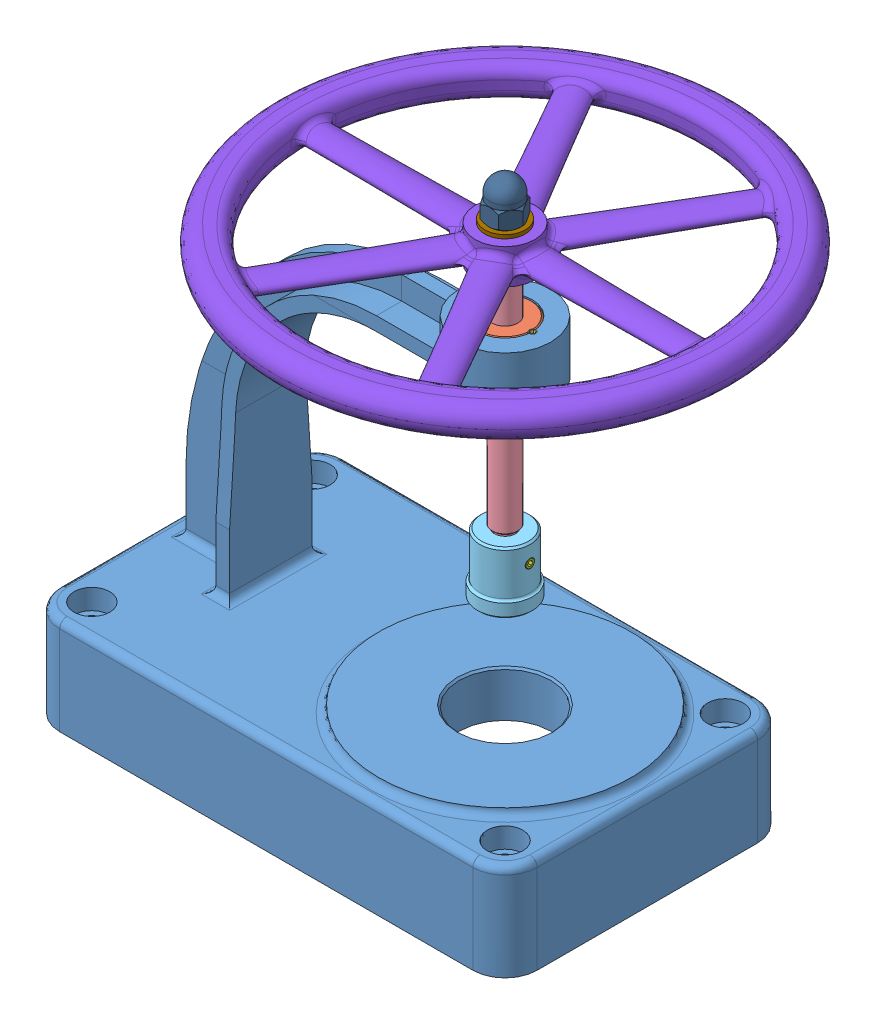
SolidWorks assembly sklop, configuration Default. Lengths in mm.
Overall size (615 613.4 500).
12 component instances, 10 part files, 33 mates.
Components (placement in the parent):
- postolje-1: postolje [Default] at (302.1555 83.8937 469.4911) size (520 480 310)
- matica-1: matica [Default] at (302.1555 493.8937 469.4911) size (70 70 70)
- vijak M8-1: vijak M8 [Default] at (272.1555 543.8937 469.4911) size (8 20 8)
- vijak M8-2: vijak M8 [Default] at (332.1555 543.8937 469.4911) size (8 20 8)
- vreteno-1: vreteno [Default] at (302.1555 323.8937 469.4911) size (36.2 353 36.2)
- glava-1: glava [Default] at (302.1555 298.8937 469.4911) x (0 0 1) z (-1 0 0) size (60 65 60)
- kuglasti oslonac-1: kuglasti oslonac [Default] at (302.1555 313.8937 469.4911) x (0 0 1) z (-1 0 0) size (21 10 21)
- vijak M10-1: vijak M10 [Default] at (274.6555 343.8937 469.4911) x (0 0 1) z (0 1 0) size (10 20 10)
- vijak M10-2: vijak M10 [Default] at (329.6555 343.8937 469.4911) x (0 0 1) z (0 -1 0) size (10 20 10)
- kolo 500-1: kolo 500 [Default] at (302.1555 632.8937 469.4911) size (500 38 500)
- podlozna plocica-1: podlozna plocica [Default] at (302.1555 651.8937 469.4911) size (44 4 44)
- matica M24-1: matica M24 [Default] at (302.1555 655.8937 469.4911) size (43.5 41.4 34.25)
Mates (geometry in assembly coordinates):
- Concentric1: concentric anti-aligned: cylinder of postolje-1 through (302.1555 83.8927 469.4911) axis (0 1 0) radius 30; cylinder of matica-1 through (302.1555 563.8937 469.4911) axis (0 -1 0) radius 30
- Coincident2: coincident aligned: plane of postolje-1 through (302.1555 563.8937 469.4911) normal (0 1 0); plane of matica-1 through (302.1555 563.8937 469.4911) normal (0 1 0)
- Coincident3: coincident aligned: plane of postolje-1 through (302.1555 83.8937 469.4911) normal (0 0 1); plane of matica-1 through (302.1555 493.8937 469.4911) normal (0 0 1)
- Concentric2: concentric anti-aligned: cylinder of postolje-1 through (272.1555 563.8937 469.4911) axis (0 1 0) radius 3.3235; cylinder of vijak M8-1 through (272.1555 563.8937 469.4911) axis (0 -1 0) radius 4
- Coincident4: coincident aligned: plane of postolje-1 through (302.1555 563.8937 469.4911) normal (0 1 0); plane of vijak M8-1 through (272.1555 563.8937 469.4911) normal (0 1 0)
- Coincident5: coincident aligned: plane of postolje-1 through (302.1555 83.8937 469.4911) normal (0 0 1); plane of vijak M8-1 through (272.1555 543.8937 469.4911) normal (0 0 1)
- Concentric3: concentric anti-aligned: cylinder of postolje-1 through (332.1555 563.8937 469.4911) axis (0 1 0) radius 3.3235; cylinder of vijak M8-2 through (332.1555 563.8937 469.4911) axis (0 -1 0) radius 4
- Coincident6: coincident aligned: plane of postolje-1 through (302.1555 563.8937 469.4911) normal (0 1 0); plane of vijak M8-2 through (332.1555 563.8937 469.4911) normal (0 1 0)
- Coincident7: coincident aligned: plane of postolje-1 through (302.1555 83.8937 469.4911) normal (0 0 1); plane of vijak M8-2 through (332.1555 543.8937 469.4911) normal (0 0 1)
- Concentric4: concentric anti-aligned: cylinder of matica-1 through (302.1555 493.8937 469.4911) axis (0 1 0) radius 14; cylinder of vreteno-1 through (302.1555 608.8937 469.4911) axis (0 -1 0) radius 14
- Coincident8: coincident aligned: plane of postolje-1 through (302.1555 83.8937 469.4911) normal (0 0 1); plane of vreteno-1 through (302.1555 323.8937 469.4911) normal (0 0 1)
- Coincident9: coincident anti-aligned: plane of glava-1 through (302.1555 313.8937 469.4911) normal (0 1 0); plane of kuglasti oslonac-1 through (302.1555 313.8937 469.4911) normal (0 -1 0)
- Concentric7: concentric anti-aligned: cylinder of glava-1 through (302.1555 313.8937 469.4911) axis (0 1 0) radius 10.5; cylinder of kuglasti oslonac-1 through (302.1555 323.8937 469.4911) axis (0 -1 0) radius 10.5
- Tangent1: tangent anti-aligned: plane of vreteno-1 through (302.1555 323.8937 469.4911) normal (0 -1 0); sphere of kuglasti oslonac-1
- Concentric8: concentric anti-aligned: cylinder of vreteno-1 through (302.1555 365.8937 469.4911) axis (0 -1 0) radius 10.5; cylinder of glava-1 through (302.1555 313.8937 469.4911) axis (0 1 0) radius 10.5
- Coincident10: coincident aligned: plane of postolje-1 through (302.1555 83.8937 469.4911) normal (0 0 1); plane of glava-1 through (302.1555 298.8937 469.4911) normal (0 0 1)
- Concentric9: concentric anti-aligned: cylinder of glava-1 through (332.1555 343.8937 469.4911) axis (-1 0 0) radius 4.188; cylinder of vijak M10-2 through (314.6555 343.8937 469.4911) axis (1 0 0) radius 5
- Tangent2: tangent aligned: cylinder of glava-1 through (302.1555 363.8937 469.4911) axis (0 -1 0) radius 27.5; plane of vijak M10-2 through (329.6555 343.8937 469.4911) normal (1 0 0)
- Parallel1: parallel anti-aligned: plane of glava-1 through (302.1555 298.8937 469.4911) normal (0 1 0); plane of vijak M10-2 through (329.6555 343.8937 469.4911) normal (0 -1 0)
- Concentric10: concentric aligned: cylinder of glava-1 through (332.1555 343.8937 469.4911) axis (-1 0 0) radius 4.188; cylinder of vijak M10-1 through (289.6555 343.8937 469.4911) axis (-1 0 0) radius 5
- Tangent3: tangent aligned: cylinder of glava-1 through (302.1555 363.8937 469.4911) axis (0 -1 0) radius 27.5; plane of vijak M10-1 through (274.6555 343.8937 469.4911) normal (-1 0 0)
- Parallel2: parallel aligned: plane of glava-1 through (302.1555 298.8937 469.4911) normal (0 1 0); plane of vijak M10-1 through (274.6555 343.8937 469.4911) normal (0 1 0)
- Coincident23: coincident aligned: plane of vreteno-1 through (302.1555 613.8937 469.4911) normal (0 -1 0); plane of kolo 500-1 through (334.6555 613.8937 469.4911) normal (0 -1 0)
- Coincident24: coincident anti-aligned: plane of vreteno-1 through (284.0555 613.8937 451.3911) normal (0 0.099504 -0.995037); plane of kolo 500-1 through (284.0555 613.8937 451.3911) normal (0 -0.099504 0.995037)
- Coincident25: coincident anti-aligned: plane of vreteno-1 through (320.2555 613.8937 487.5911) normal (0.995037 0.099504 0); plane of kolo 500-1 through (320.2555 613.8937 451.3911) normal (-0.995037 -0.099504 0)
- Concentric11: concentric aligned: cylinder of vreteno-1 through (302.1555 676.8937 469.4911) axis (0 -1 0) radius 12; cylinder of podlozna plocica-1 through (302.1555 655.8937 469.4911) axis (0 -1 0) radius 12.5
- Coincident26: coincident anti-aligned: plane of kolo 500-1 through (302.1555 651.8937 469.4911) normal (0 1 0); plane of podlozna plocica-1 through (302.1555 651.8937 469.4911) normal (0 -1 0)
- Coincident27: coincident aligned: plane of kolo 500-1 through (302.1555 632.8937 469.4911) normal (0 0 1); plane of podlozna plocica-1 through (302.1555 651.8937 469.4911) normal (0 0 1)
- Concentric12: concentric aligned: cylinder of vreteno-1 through (302.1555 676.8937 469.4911) axis (0 -1 0) radius 12; cylinder of matica M24-1 through (302.1555 655.8937 469.4911) axis (0 -1 0) radius 12
- Coincident28: coincident anti-aligned: plane of podlozna plocica-1 through (302.1555 655.8937 469.4911) normal (0 1 0); plane of matica M24-1 through (302.1555 655.8937 469.4911) normal (0 -1 0)
- Coincident29: coincident aligned: plane of kolo 500-1 through (302.1555 632.8937 469.4911) normal (0 0 1); plane of matica M24-1 through (302.1555 655.8937 469.4911) normal (0 0 1)
- Distance1: distance = 130 mm anti-aligned: plane of matica-1 through (302.1555 493.8937 469.4911) normal (0 -1 0); plane of glava-1 through (302.1555 363.8937 469.4911) normal (0 1 0)
- Coincident31: coincident aligned: plane of glava-1 through (302.1555 298.8937 469.4911) normal (-1 0 0); plane of kuglasti oslonac-1 through (302.1555 313.8937 469.4911) normal (-1 0 0)
